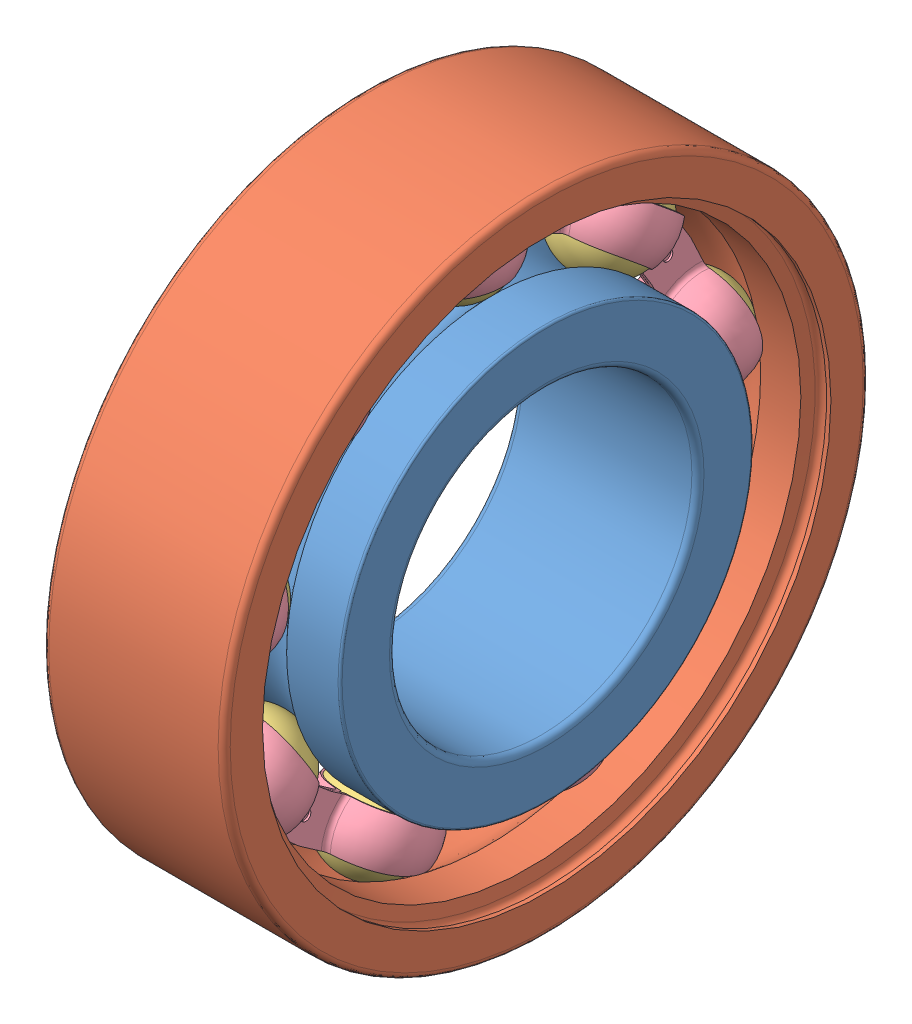
SolidWorks assembly 6002 - bearing, configuration Default. Lengths in mm.
Overall size (9 32 32).
13 component instances, 4 part files, 12 mates.
Components (placement in the parent):
- 6002 - core-1: 6002 - core [Default] at origin size (9 20.5 20.5)
- 6002 - outer-1: 6002 - outer [Default] x (0 0 1) z (-1 0 0) size (32 32 9)
- 6002 - ball-1: 6002 - ball [Default] at (4.5 0 0) size (4.76 4.76 4.76)
- 6002 - ball-2: 6002 - ball [Default] at (4.5 0 0) x (1 0 0) z (0 -0.642788 0.766044) size (4.76 4.76 4.76)
- 6002 - ball-3: 6002 - ball [Default] at (4.5 0 0) x (1 0 0) z (0 -0.984808 0.173648) size (4.76 4.76 4.76)
- 6002 - ball-4: 6002 - ball [Default] at (4.5 0 0) x (1 0 0) z (0 -0.866025 -0.5) size (4.76 4.76 4.76)
- 6002 - ball-5: 6002 - ball [Default] at (4.5 0 0) x (1 0 0) z (0 -0.34202 -0.939693) size (4.76 4.76 4.76)
- 6002 - ball-6: 6002 - ball [Default] at (4.5 0 0) x (1 0 0) z (0 0.34202 -0.939693) size (4.76 4.76 4.76)
- 6002 - ball-7: 6002 - ball [Default] at (4.5 0 0) x (1 0 0) z (0 0.866025 -0.5) size (4.76 4.76 4.76)
- 6002 - ball-8: 6002 - ball [Default] at (4.5 0 0) x (1 0 0) z (0 0.984808 0.173648) size (4.76 4.76 4.76)
- 6002 - ball-9: 6002 - ball [Default] at (4.5 0 0) x (1 0 0) z (0 0.642788 0.766044) size (4.76 4.76 4.76)
- 6002 - cage-1: 6002 - cage [Default] at (4.5 0 0) x (0 0 -1) z (1 0 0) size (26 26 2.62)
- 6002 - cage-2: 6002 - cage [Default] at (4.5 0 0) x (0 0 1) z (-1 0 0) size (26 26 2.62)
Mates (geometry in assembly coordinates):
- Coincident2: coincident aligned: plane of 6002 - core-1 through (0 0 0) normal (0 0 1); plane of assembly through (0 0 0) normal (0 0 1)
- Coincident3: coincident aligned: plane of 6002 - core-1 through (0 0 0) normal (0 1 0); plane of assembly through (0 0 0) normal (0 1 0)
- Coincident4: coincident aligned: plane of 6002 - core-1 through (0 0 0) normal (1 0 0); plane of assembly through (0 0 0) normal (1 0 0)
- Coincident5: coincident aligned: plane of 6002 - outer-1 through (0 0 0) normal (0 0 1); plane of assembly through (0 0 0) normal (0 0 1)
- Coincident6: coincident anti-aligned: plane of 6002 - outer-1 through (0 0 0) normal (-1 0 0); plane of assembly through (0 0 0) normal (1 0 0)
- Coincident7: coincident aligned: plane of 6002 - outer-1; plane of assembly through (0 0 0) normal (0 1 0)
- Coincident8: coincident aligned: plane of 6002 - ball-1 through (4.5 0 0) normal (0 1 0); plane of assembly through (0 0 0) normal (0 1 0)
- Coincident9: coincident aligned: plane of 6002 - ball-1 through (4.5 0 0) normal (0 0 1); plane of assembly through (0 0 0) normal (0 0 1)
- Distance1: distance = 4.5 mm aligned: plane of 6002 - ball-1 through (4.5 0 0) normal (1 0 0); plane of assembly through (0 0 0) normal (1 0 0)
- Distance2: distance = 4.5 mm aligned: plane of 6002 - cage-1 through (4.5 0 0) normal (1 0 0); plane of assembly through (0 0 0) normal (1 0 0)
- Coincident12: coincident aligned: plane of 6002 - cage-1; plane of assembly through (0 0 0) normal (0 1 0)
- Coincident13: coincident anti-aligned: plane of 6002 - cage-1 through (4.5 0 0) normal (0 0 -1); plane of assembly through (0 0 0) normal (0 0 1)
